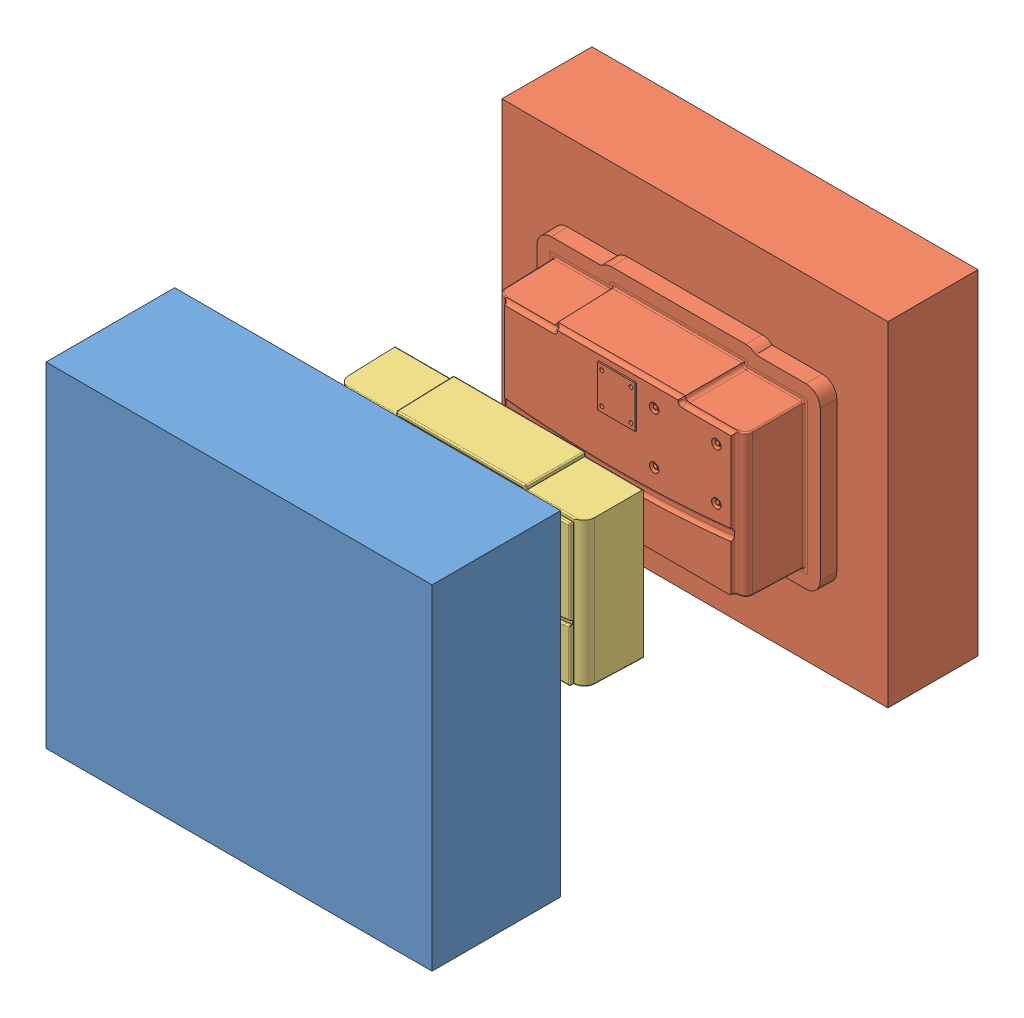
SolidWorks assembly Assem2, configuration Default. Lengths in mm.
Overall size (300 260 424.26).
3 component instances, 3 part files, 8 mates.
Components (placement in the parent):
- metal final face_moldable-Cavity-1: metal final face_moldable-Cavity [Default] at (4.5731 -7.3652 78.807) size (300 260 100.02)
- metal final face_moldable-Core-2: metal final face_moldable-Core [Default] at (4.5731 -7.3652 -15.4573) size (300 260 131.12)
- final face_moldable-3: final face_moldable [Default] at (3.0164 -7.4014 105.2141) size (192.48 116.71 48.58)
Mates (geometry in assembly coordinates):
- Coincident9: coincident aligned: plane of metal final face_moldable-Cavity-1 through (154.5731 122.6348 324.5468) normal (1 0 0); plane of metal final face_moldable-Core-2 through (154.5731 122.6348 70.2826) normal (1 0 0)
- Coincident10: coincident aligned: plane of metal final face_moldable-Cavity-1 through (-145.4269 122.6348 324.5468) normal (-1 0 0); plane of metal final face_moldable-Core-2 through (-145.4269 122.6348 70.2826) normal (-1 0 0)
- Coincident11: coincident aligned: plane of metal final face_moldable-Cavity-1 through (154.5731 122.6348 324.5468) normal (0 1 0); plane of metal final face_moldable-Core-2 through (154.5731 122.6348 70.2826) normal (0 1 0)
- Coincident12: coincident aligned: plane of metal final face_moldable-Cavity-1 through (154.5731 122.6348 324.5468) normal (1 0 0); plane of metal final face_moldable-Core-2 through (154.5731 122.6348 70.2826) normal (1 0 0)
- Coincident13: coincident aligned: plane of metal final face_moldable-Cavity-1 through (154.5731 -137.3652 324.5468) normal (0 -1 0); plane of metal final face_moldable-Core-2 through (154.5731 -137.3652 70.2826) normal (0 -1 0)
- Coincident14: coincident aligned: plane of metal final face_moldable-Cavity-1 through (-145.4269 122.6348 324.5468) normal (-1 0 0); plane of metal final face_moldable-Core-2 through (-145.4269 122.6348 70.2826) normal (-1 0 0)
- Coincident18: coincident anti-aligned: plane of metal final face_moldable-Core-2 through (4.5853 -62.6327 30.1244) normal (0 -0.999848 0.017452); plane of final face_moldable-3 through (3.0188 -60.5352 150.2898) normal (0 0.999848 -0.017452)
- Coincident19: coincident anti-aligned: plane of metal final face_moldable-Core-2 through (-91.5952 -7.4022 30.1244) normal (-0.999848 0 0.017452); plane of final face_moldable-3 through (-89.4977 -7.4087 150.2898) normal (0.999848 0 -0.017452)
